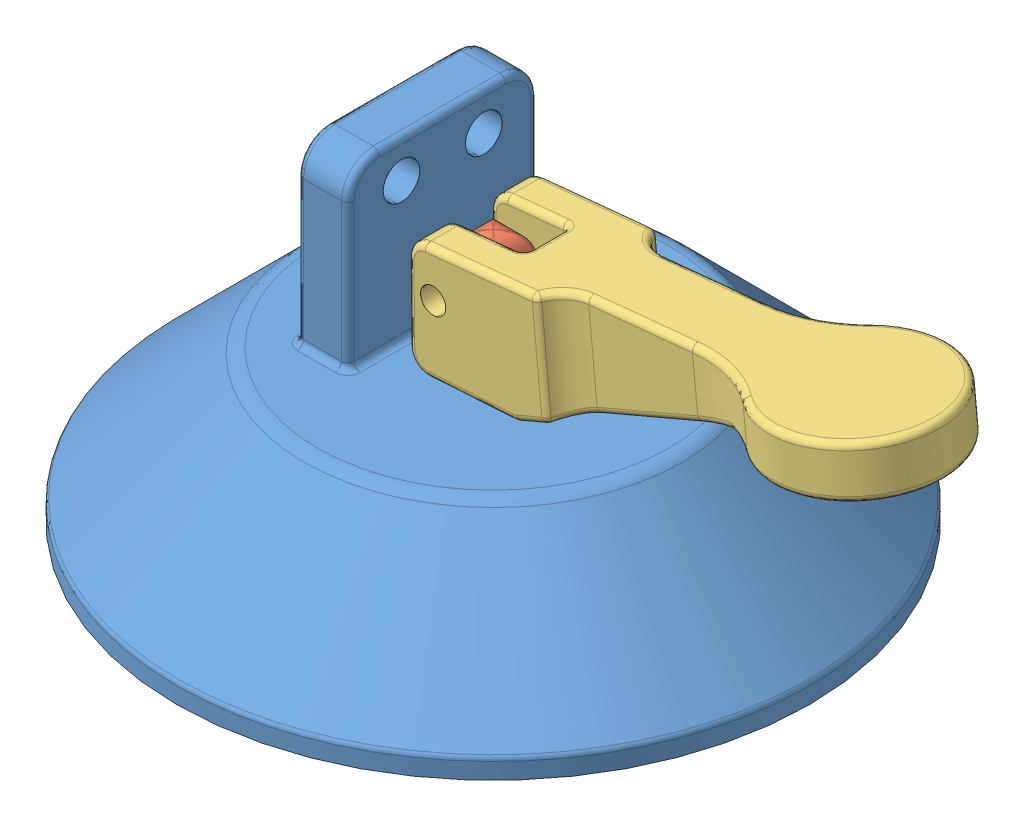
SolidWorks assembly 100LWBN, configuration Default. Lengths in mm.
Overall size (122.12 52 100).
3 component instances, 3 part files, 8 mates.
Components (placement in the parent):
- 100LWBN_suction_pad-1: 100LWBN_suction_pad [Default] at origin size (100 52 100)
- 100LWBN_shaft-1: 100LWBN_shaft [Default] at (0 35.0737 0) size (7 20 7)
- 100LWBN_handle-1: 100LWBN_handle [Default] at (0 35.0737 0) x (-0.997983 -0.063481 0) z (0 0 -1) size (75.98 20.58 26)
Mates (geometry in assembly coordinates):
- Coincident1: coincident aligned: plane of 100LWBN_suction_pad-1 through (0 0 0) normal (1 0 0); plane of assembly through (0 0 0) normal (1 0 0)
- Coincident2: coincident aligned: plane of 100LWBN_suction_pad-1 through (0 0 0) normal (0 1 0); plane of assembly through (0 0 0) normal (0 1 0)
- Coincident3: coincident aligned: plane of 100LWBN_suction_pad-1 through (0 0 0) normal (0 0 1); plane of assembly through (0 0 0) normal (0 0 1)
- Coincident4: coincident aligned: plane of 100LWBN_suction_pad-1 through (0 0 0) normal (0 0 1); plane of 100LWBN_shaft-1 through (0 35.0737 0) normal (0 0 1)
- Coincident5: coincident aligned: plane of 100LWBN_suction_pad-1 through (0 0 0) normal (1 0 0); plane of 100LWBN_shaft-1 through (0 35.0737 0) normal (1 0 0)
- Concentric1: concentric aligned: cylinder of 100LWBN_shaft-1 through (0 35.0737 3.5) axis (0 0 -1) radius 2; cylinder of 100LWBN_handle-1 through (0 35.0737 13) axis (0 0 -1) radius 2
- Coincident6: coincident anti-aligned: plane of 100LWBN_shaft-1 through (0 35.0737 0) normal (0 0 1); plane of 100LWBN_handle-1 through (0 35.0737 0) normal (0 0 -1)
- Tangent1: tangent anti-aligned: plane of 100LWBN_suction_pad-1 through (0 24 0) normal (0 1 0); cylinder of 100LWBN_handle-1 through (-0.9044 27 -13) axis (0 0 1) radius 3
